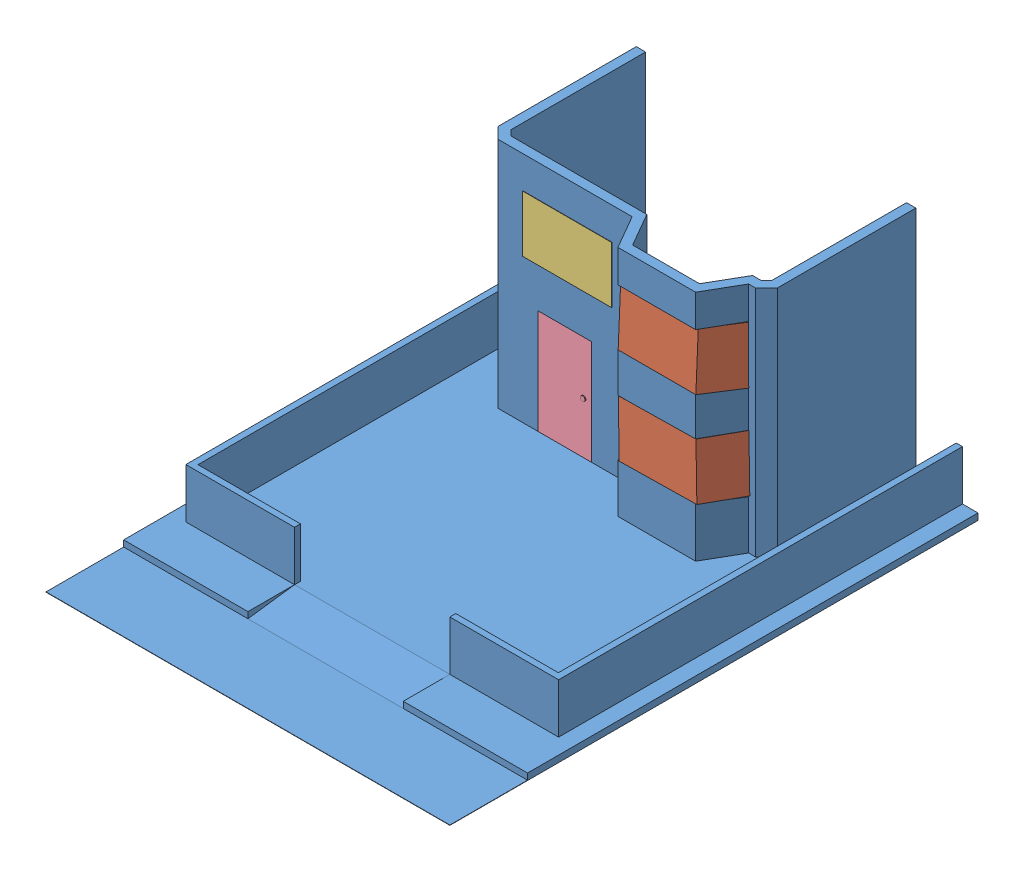
SolidWorks assembly pues la vista, configuration Predeterminado. Lengths in mm.
Overall size (13000 7710 17000).
5 component instances, 4 part files, 7 mates.
Components (placement in the parent):
- si-1: si [Predeterminado] at (-4345.2442 -3875.055 17000) size (13000 7710 17000)
- vidrio-2: vidrio [Predeterminado] at (-3216.8614 -2100.6991 13682.6758) x (0.999868 0.016256 0) z (-0.016256 0.999868 0) size (3747.3 1235.31 1810)
- vidrio-3: vidrio [Predeterminado] at (-3250.3657 950.0978 13683.3327) x (1 0 0) z (0 0.999072 -0.043062) size (3747.3 1235.31 1810)
- vidrio2-1: vidrio2 [Predeterminado] at (-6451.934 2798.5636 12745.8236) x (1 0 0) z (0 -1 0) size (2864.93 300 1817.97)
- puerta-1: puerta [Predeterminado] at (-5732.5865 -2004.8768 13008.3333) size (1717.05 3362.83 330)
Mates (geometry in assembly coordinates):
- Coincidente3: coincident: line of assembly; line of assembly; line of si-1 through (-3544.4324 -2106.0247 14390.8651) axis (0.999868 0.016256 0); line of vidrio-2 through (-3503.3743 -2105.3572 14390.8651) axis (0.999868 0.016256 0)
- Coincidente4: coincident: line of assembly; line of assembly; line of si-1 through (-3544.4324 980.5936 14390.8651) axis (1 0 0); line of vidrio-3 through (-3536.9165 980.5936 14390.8651) axis (1 0 0)
- Coincidente5: coincident: plane of assembly; plane of assembly; plane of si-1 through (-4824.1205 980.5936 12768.3333) normal (0 1 0); plane of vidrio2-1 through (-6451.934 980.5936 12745.8236) normal (0 -1 0)
- Coincidente6: coincident: plane of assembly; plane of assembly; plane of si-1 through (-7689.0512 980.5936 12768.3333) normal (1 0 0); plane of vidrio2-1 through (-7689.0512 980.5936 13319.5404) normal (-1 0 0)
- Coincidente7: coincident: plane of assembly; plane of assembly; plane of si-1 through (-7192.2418 -302.2294 8500) normal (0 -1 0); plane of puerta-1 through (-7192.2418 -302.2294 13308.3333) normal (0 1 0)
- Coincidente8: coincident: plane of assembly; plane of assembly; plane of si-1 through (-7192.2418 -3665.055 8500) normal (1 0 0); plane of puerta-1 through (-7192.2418 -302.2294 13308.3333) normal (-1 0 0)
- Coincidente9: coincident: line of assembly; line of assembly; line of si-1 through (-5475.1941 -302.2294 13308.3333) axis (-1 0 0); line of puerta-1 through (-5475.1918 -302.2294 13308.3333) axis (-1 0 0)
